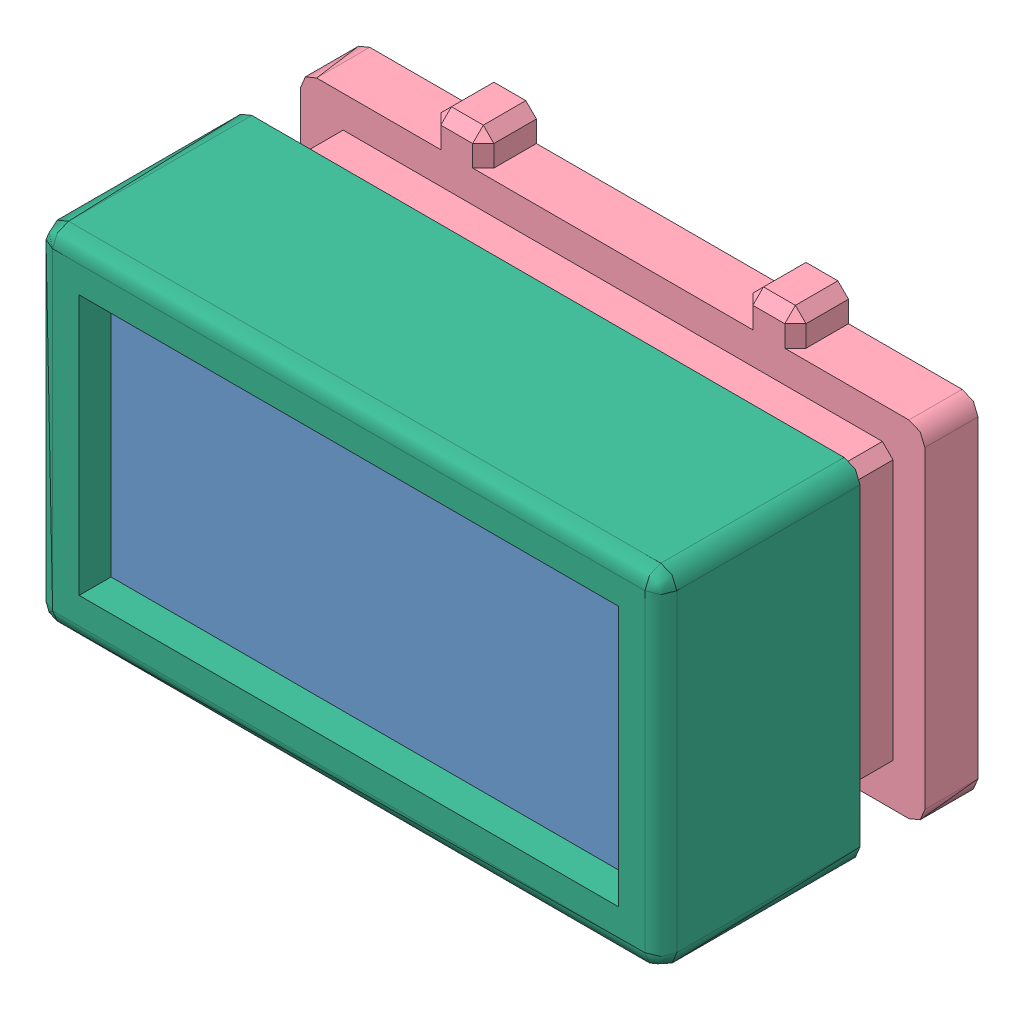
SolidWorks assembly JETT Select Indicator, configuration NOSE. Lengths in mm.
Overall size (14.92 9.78 7.94).
7 component instances, 6 part files, 8 mates.
Components (placement in the parent):
- JETT Select Indicator Legend Cover-1: JETT Select Indicator Legend Cover [BLANK] at (20.4563 66.7606 -0.762) x (-1 0 0) z (0 0 -1) size (13.4 6.73 0.76)
- JETT Select Indicator Legend-1: JETT Select Indicator Legend [NOSE] at (30.3037 69.0358 -1.524) x (-1 0 0) z (0 0 -1) size (13.4 6.73 0.13)
- JETT Select Indicator Legend Diffuser-1: JETT Select Indicator Legend Diffuser [Green] at (-0.8961 156.0041 -1.651) x (1 0 0) z (0 0 -1) size (13.4 6.73 0.13)
- JETT Select Indicator Standoff-1: JETT Select Indicator Standoff [Default] at (-0.8961 156.0041 -1.778) x (1 0 0) z (0 0 -1) size (14.92 9.78 5.8)
- IN-S63AT5UW - LED, 0603, WHITE, 3V, 5mA, 900mcd-1: IN-S63AT5UW - LED, 0603, WHITE, 3V, 5mA, 900mcd [Default] at (26.8542 -43.18 -7.9311) x (0 -1 0) z (0 0 1) size (0.79 1.61 0.71)
- IN-S63AT5UW - LED, 0603, WHITE, 3V, 5mA, 900mcd-2: IN-S63AT5UW - LED, 0603, WHITE, 3V, 5mA, 900mcd [Default] at (17.5958 -43.18 -7.9311) x (0 -1 0) z (0 0 1) size (0.79 1.61 0.71)
- JETT Select Indicator Bezel-1: JETT Select Indicator Bezel [Default] at origin size (14.92 8.26 4.76)
Mates (geometry in assembly coordinates):
- ProfileCenter9: profile center anti-aligned: plane of JETT Select Indicator Legend-1 through (30.3037 69.0358 -1.524) normal (0 0 1); plane of JETT Select Indicator Legend Cover-1 through (20.4563 66.7606 -1.524) normal (0 0 -1)
- ProfileCenter10: profile center anti-aligned: plane of JETT Select Indicator Legend Cover-1 through (20.4563 66.7606 -0.762) normal (0 0 1); plane of JETT Select Indicator Bezel-1 through (0 0 -0.762) normal (0 0 -1)
- ProfileCenter8: profile center anti-aligned: plane of JETT Select Indicator Legend Diffuser-1 through (-0.8961 156.0041 -1.651) normal (0 0 1); plane of JETT Select Indicator Legend-1 through (30.3037 69.0358 -1.651) normal (0 0 -1)
- Width19: width anti-aligned: plane of JETT Select Indicator Standoff-1 through (15.5258 -40.5765 -7.5819) normal (0 -1 0); plane of JETT Select Indicator Standoff-1 through (28.9242 -45.7835 -7.5819) normal (0 1 0); plane of IN-S63AT5UW - LED, 0603, WHITE, 3V, 5mA, 900mcd-1 through (26.0604 -42.7863 -7.639) normal (0 1 0); plane of IN-S63AT5UW - LED, 0603, WHITE, 3V, 5mA, 900mcd-1 through (27.6479 -43.5737 -7.639) normal (0 -1 0)
- Distance5: distance = 0.508 mm anti-aligned: plane of IN-S63AT5UW - LED, 0603, WHITE, 3V, 5mA, 900mcd-1 through (27.6542 -42.7838 -7.6266) normal (1 0 0); plane of JETT Select Indicator Standoff-1 through (28.1623 -39.8145 -7.5819) normal (-1 0 0)
- Distance6: distance = 0.508 mm anti-aligned: plane of IN-S63AT5UW - LED, 0603, WHITE, 3V, 5mA, 900mcd-2 through (16.7958 -42.7838 -7.6266) normal (-1 0 0); plane of JETT Select Indicator Standoff-1 through (16.2877 -46.5455 -7.5819) normal (1 0 0)
- Coincident100: coincident aligned: plane of IN-S63AT5UW - LED, 0603, WHITE, 3V, 5mA, 900mcd-1 through (26.0452 -42.7838 -7.9375) normal (0 0 -1); plane of IN-S63AT5UW - LED, 0603, WHITE, 3V, 5mA, 900mcd-2 through (16.7869 -42.7838 -7.9375) normal (0 0 -1)
- Coincident101: coincident aligned: plane of IN-S63AT5UW - LED, 0603, WHITE, 3V, 5mA, 900mcd-1 through (27.6479 -43.5737 -7.639) normal (0 -1 0); plane of IN-S63AT5UW - LED, 0603, WHITE, 3V, 5mA, 900mcd-2 through (18.3896 -43.5737 -7.639) normal (0 -1 0)
